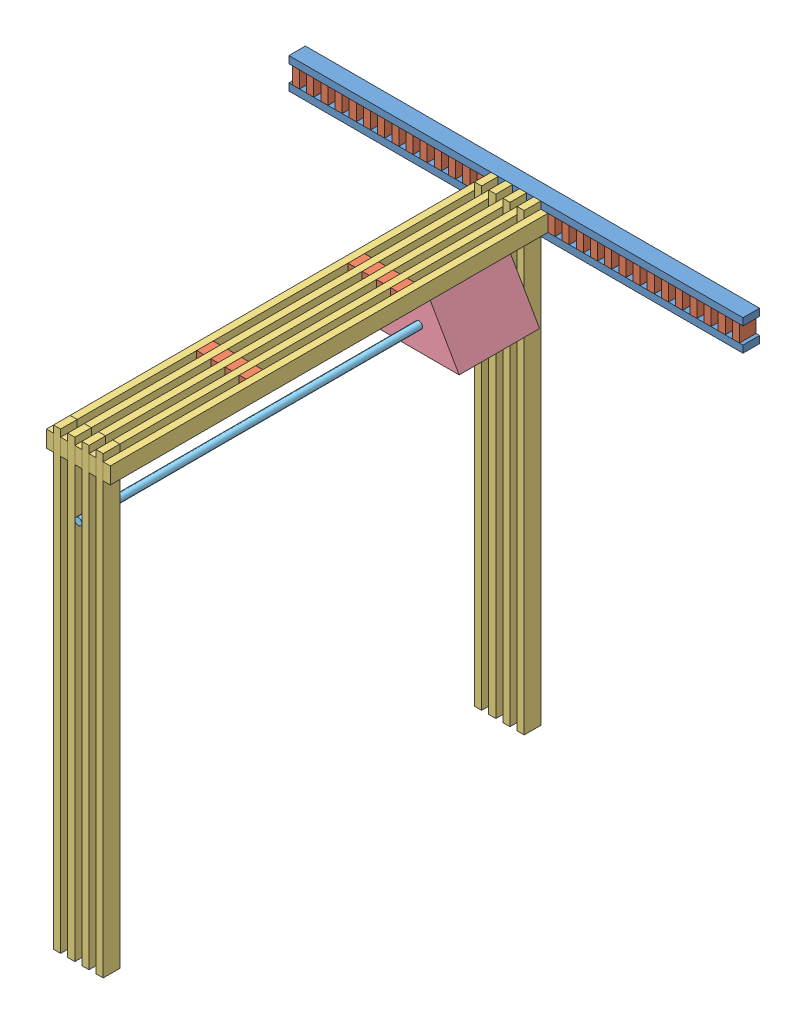
SolidWorks assembly assembled, configuration Default. Lengths in mm.
Overall size (2438.4 2438.4 2438.4).
65 component instances, 5 part files, 11 mates.
Components (placement in the parent):
- truss-1: truss [Default] at (-1882.1813 1147.4716 985.8494) size (2438.4 2438.4 2438.4)
  - foot_plus_side_post-1: foot_plus_side_post [Default] at (-927.419 -1332.037 -3654.4904) size (2438.4 165.1 2438.4)
    - foot_post-1: foot_post [Default] at (1347.1514 1068.5792 1779.6361) size (2438.4 165.1 88.9)
      - 2x4_foot-1: 2x4_foot [Default] at (-704.8006 1778.2043 2380.3143) size (2438.4 38.1 88.9)
      - 2x4_foot-2: 2x4_foot [Default] at (-704.8006 1689.3043 2469.2143) x (1 0 0) z (0 0 -1) size (2438.4 38.1 88.9)
      - 4x4x2_gusset-32: 4x4x2_gusset [Default] at (571.5494 1689.3043 2380.3143) x (0 1 0) z (0 0 1) size (88.9 38.1 88.9)
      - 4x4x2_gusset-33: 4x4x2_gusset [Default] at (495.3494 1689.3043 2380.3143) x (0 1 0) z (0 0 1) size (88.9 38.1 88.9)
      - 4x4x2_gusset-34: 4x4x2_gusset [Default] at (419.1494 1689.3043 2380.3143) x (0 1 0) z (0 0 1) size (88.9 38.1 88.9)
      - 4x4x2_gusset-35: 4x4x2_gusset [Default] at (342.9494 1689.3043 2380.3143) x (0 1 0) z (0 0 1) size (88.9 38.1 88.9)
      - 4x4x2_gusset-36: 4x4x2_gusset [Default] at (266.7494 1689.3043 2380.3143) x (0 1 0) z (0 0 1) size (88.9 38.1 88.9)
      - 4x4x2_gusset-37: 4x4x2_gusset [Default] at (190.5494 1689.3043 2380.3143) x (0 1 0) z (0 0 1) size (88.9 38.1 88.9)
      - 4x4x2_gusset-38: 4x4x2_gusset [Default] at (114.3494 1689.3043 2380.3143) x (0 1 0) z (0 0 1) size (88.9 38.1 88.9)
      - 4x4x2_gusset-39: 4x4x2_gusset [Default] at (38.1494 1689.3043 2380.3143) x (0 1 0) z (0 0 1) size (88.9 38.1 88.9)
      - 4x4x2_gusset-40: 4x4x2_gusset [Default] at (-38.0506 1689.3043 2380.3143) x (0 1 0) z (0 0 1) size (88.9 38.1 88.9)
      - 4x4x2_gusset-41: 4x4x2_gusset [Default] at (-114.2506 1689.3043 2380.3143) x (0 1 0) z (0 0 1) size (88.9 38.1 88.9)
      - 4x4x2_gusset-42: 4x4x2_gusset [Default] at (-190.4506 1689.3043 2380.3143) x (0 1 0) z (0 0 1) size (88.9 38.1 88.9)
      - 4x4x2_gusset-43: 4x4x2_gusset [Default] at (-266.6506 1689.3043 2380.3143) x (0 1 0) z (0 0 1) size (88.9 38.1 88.9)
      - 4x4x2_gusset-44: 4x4x2_gusset [Default] at (-342.8506 1689.3043 2380.3143) x (0 1 0) z (0 0 1) size (88.9 38.1 88.9)
      - 4x4x2_gusset-45: 4x4x2_gusset [Default] at (-419.0506 1689.3043 2380.3143) x (0 1 0) z (0 0 1) size (88.9 38.1 88.9)
      - 4x4x2_gusset-46: 4x4x2_gusset [Default] at (-495.2506 1689.3043 2380.3143) x (0 1 0) z (0 0 1) size (88.9 38.1 88.9)
      - 4x4x2_gusset-47: 4x4x2_gusset [Default] at (-571.4506 1689.3043 2380.3143) x (0 1 0) z (0 0 1) size (88.9 38.1 88.9)
      - 4x4x2_gusset-48: 4x4x2_gusset [Default] at (-647.6506 1689.3043 2380.3143) x (0 1 0) z (0 0 1) size (88.9 38.1 88.9)
      - 4x4x2_gusset-49: 4x4x2_gusset [Default] at (647.7494 1689.3043 2380.3143) x (0 1 0) z (0 0 1) size (88.9 38.1 88.9)
      - 4x4x2_gusset-50: 4x4x2_gusset [Default] at (723.9494 1689.3043 2380.3143) x (0 1 0) z (0 0 1) size (88.9 38.1 88.9)
      - 4x4x2_gusset-51: 4x4x2_gusset [Default] at (800.1494 1689.3043 2380.3143) x (0 1 0) z (0 0 1) size (88.9 38.1 88.9)
      - 4x4x2_gusset-52: 4x4x2_gusset [Default] at (876.3494 1689.3043 2380.3143) x (0 1 0) z (0 0 1) size (88.9 38.1 88.9)
      - 4x4x2_gusset-53: 4x4x2_gusset [Default] at (952.5494 1689.3043 2380.3143) x (0 1 0) z (0 0 1) size (88.9 38.1 88.9)
      - 4x4x2_gusset-54: 4x4x2_gusset [Default] at (1028.7494 1689.3043 2380.3143) x (0 1 0) z (0 0 1) size (88.9 38.1 88.9)
      - 4x4x2_gusset-55: 4x4x2_gusset [Default] at (1104.9494 1689.3043 2380.3143) x (0 1 0) z (0 0 1) size (88.9 38.1 88.9)
      - 4x4x2_gusset-56: 4x4x2_gusset [Default] at (1181.1494 1689.3043 2380.3143) x (0 1 0) z (0 0 1) size (88.9 38.1 88.9)
      - 4x4x2_gusset-57: 4x4x2_gusset [Default] at (1257.3494 1689.3043 2380.3143) x (0 1 0) z (0 0 1) size (88.9 38.1 88.9)
      - 4x4x2_gusset-58: 4x4x2_gusset [Default] at (1333.5494 1689.3043 2380.3143) x (0 1 0) z (0 0 1) size (88.9 38.1 88.9)
      - 4x4x2_gusset-59: 4x4x2_gusset [Default] at (1409.7494 1689.3043 2380.3143) x (0 1 0) z (0 0 1) size (88.9 38.1 88.9)
      - 4x4x2_gusset-60: 4x4x2_gusset [Default] at (1485.9494 1689.3043 2380.3143) x (0 1 0) z (0 0 1) size (88.9 38.1 88.9)
      - 4x4x2_gusset-61: 4x4x2_gusset [Default] at (1562.1494 1689.3043 2380.3143) x (0 1 0) z (0 0 1) size (88.9 38.1 88.9)
      - 4x4x2_gusset-62: 4x4x2_gusset [Default] at (1638.3494 1689.3043 2380.3143) x (0 1 0) z (0 0 1) size (88.9 38.1 88.9)
      - 4x4x2_gusset-63: 4x4x2_gusset [Default] at (1714.5494 1689.3043 2380.3143) x (0 1 0) z (0 0 1) size (88.9 38.1 88.9)
    - 18x4_female_post-1: 18x4_female_post [Default] at (4665.928 6948.7926 3132.4615) x (0 0 1) z (0 -1 0) size (2438.4 342.9 88.9)
      - 6x4_female_post-1: 6x4_female_post [Default] at (1617.4053 951.3945 1716.6403) size (2438.4 114.3 88.9)
        - 2x4-1: 2x4 [Default] at (-589.9165 1681.5327 2385.3688) size (2438.4 38.1 88.9)
        - 4x4x2_gusset-1: 4x4x2_gusset [Default] at (178.4335 1719.6327 2385.3688) size (88.9 38.1 88.9)
        - 4x4x2_gusset-2: 4x4x2_gusset [Default] at (991.2335 1719.6327 2385.3688) size (88.9 38.1 88.9)
        - 2x4-2: 2x4 [Default] at (-589.9165 1757.7327 2385.3688) size (2438.4 38.1 88.9)
      - 6x4_female_post-2: 6x4_female_post [Default] at (1617.4053 1103.7945 1716.6403) size (2438.4 114.3 88.9)
        - 2x4-1: 2x4 [Default] at (-589.9165 1681.5327 2385.3688) size (2438.4 38.1 88.9)
        - 4x4x2_gusset-1: 4x4x2_gusset [Default] at (178.4335 1719.6327 2385.3688) size (88.9 38.1 88.9)
        - 4x4x2_gusset-2: 4x4x2_gusset [Default] at (991.2335 1719.6327 2385.3688) size (88.9 38.1 88.9)
        - 2x4-2: 2x4 [Default] at (-589.9165 1757.7327 2385.3688) size (2438.4 38.1 88.9)
      - 4x4x2_gusset-1: 4x4x2_gusset [Default] at (1795.8388 2747.2272 4102.0091) size (88.9 38.1 88.9)
      - 4x4x2_gusset-2: 4x4x2_gusset [Default] at (2608.6388 2747.2272 4102.0091) size (88.9 38.1 88.9)
      - 2x4-1: 2x4 [Default] at (1027.4888 2937.7272 4102.0091) size (2438.4 38.1 88.9)
      - 4x4x2_gusset-3: 4x4x2_gusset [Default] at (1795.8388 2899.6272 4102.0091) size (88.9 38.1 88.9)
      - 4x4x2_gusset-4: 4x4x2_gusset [Default] at (2608.6388 2899.6272 4102.0091) size (88.9 38.1 88.9)
  - truss_beam-1: truss_beam [Default] at (-539.4757 988.8329 -1308.4501) x (0 -1 0) z (0 0 1) size (2438.4 266.7 88.9)
    - 2x4-1: 2x4 [Default] at (-564.0137 1340.2575 1902.8101) size (2438.4 38.1 88.9)
    - 2x4-2: 2x4 [Default] at (-564.0137 1416.4575 1902.8101) size (2438.4 38.1 88.9)
    - 2x4-3: 2x4 [Default] at (-564.0137 1492.6575 1902.8101) size (2438.4 38.1 88.9)
    - 2x4-4: 2x4 [Default] at (-564.0137 1568.8575 1902.8101) size (2438.4 38.1 88.9)
  - truss_beam-2: truss_beam [Default] at (2407.7393 -321.5397 952.1499) x (0 1 0) z (0 0 1) size (2438.4 266.7 88.9)
    - 2x4-1: 2x4 [Default] at (-564.0137 1340.2575 1902.8101) size (2438.4 38.1 88.9)
    - 2x4-2: 2x4 [Default] at (-564.0137 1416.4575 1902.8101) size (2438.4 38.1 88.9)
    - 2x4-3: 2x4 [Default] at (-564.0137 1492.6575 1902.8101) size (2438.4 38.1 88.9)
    - 2x4-4: 2x4 [Default] at (-564.0137 1568.8575 1902.8101) size (2438.4 38.1 88.9)
- triangle_17-1: triangle_17 [Default] at (-948.0495 2566.9682 1669.1094) x (1 0 0) z (0 -1 0) size (431.8 431.8 373.95)
- pvc_rod-1: pvc_rod [Default] at (-948.0495 2317.6683 1491.3094) x (-0.923728 -0.383049 0) z (-0.383049 0.923728 0) size (38.1 2438.4 38.1)
Mates (geometry in assembly coordinates):
- Coincident1: coincident: plane of truss-1/truss_beam-1/2x4-3 through (-890.8995 2700.3182 1669.1094) normal (0 0 1); plane of triangle_17-1 through (-948.0495 2573.3182 1669.1094) normal (0 0 -1)
- Coincident2: coincident: plane of truss-1/foot_plus_side_post-1/18x4_female_post-1/6x4_female_post-2/2x4-1 through (-967.0995 2573.3182 1491.3094) normal (0 -1 0); plane of ? through (-928.9995 2573.3182 3840.8094) normal (0 1 0)
- Coincident3: coincident: plane of truss-1/truss_beam-2/2x4-3 through (-967.0995 261.9182 3840.8094) normal (1 0 0); plane of ? through (-967.0995 2573.3182 3840.8094) normal (-1 0 0)
- Coincident4: coincident: plane of truss-1/foot_plus_side_post-1/18x4_female_post-1/6x4_female_post-2/2x4-1 through (-967.0995 2662.2182 3929.7094) normal (0 0 1); plane of ? through (-928.9995 2573.3182 3929.7094) normal (0 0 1)
- Coincident5: coincident: plane of ? through (-928.9995 2573.3182 3929.7094) normal (0 0 1); plane of pvc_rod-1 through (-925.8496 2141.5182 3929.7094) normal (0 0 1)
- Tangent1: tangent: plane of ? through (-928.9995 2160.5682 3840.8094) normal (0 -1 0); cylinder of pvc_rod-1 through (-925.8496 2141.5182 3929.7094) axis (0 0 -1) radius 19.05
- Coincident6: coincident: circle of triangle_17-1; cylinder of pvc_rod-1 through (-948.0495 2324.0183 3929.7094) axis (0 0 -1) radius 19.05
- Parallel3: parallel: plane of truss-1/truss_beam-1/2x4-3 through (-890.8995 261.9182 1580.2094) normal (0 -1 0); plane of triangle_17-1 through (-1163.9495 2199.3684 2100.9094) normal (0 -1 0)
- Tangent2: tangent: plane of truss-1/truss_beam-2/2x4-3 through (-967.0995 261.9182 3840.8094) normal (1 0 0); cylinder of pvc_rod-1 through (-948.0495 2324.0183 3929.7094) axis (0 0 -1) radius 19.05
- Coincident10: coincident: plane of truss-1/truss_beam-2/2x4-3 through (-1005.1995 261.9182 3929.7094) normal (0 0 1); plane of pvc_rod-1 through (-948.0495 2324.0183 3929.7094) normal (0 0 1)
- Distance2: distance = 6.35 mm: plane of truss-1/foot_plus_side_post-1/18x4_female_post-1/6x4_female_post-2/2x4-1 through (-967.0995 2573.3182 1491.3094) normal (0 -1 0); line of triangle_17-1 through (-948.0495 2566.9682 2100.9094) axis (0 0 -1)
